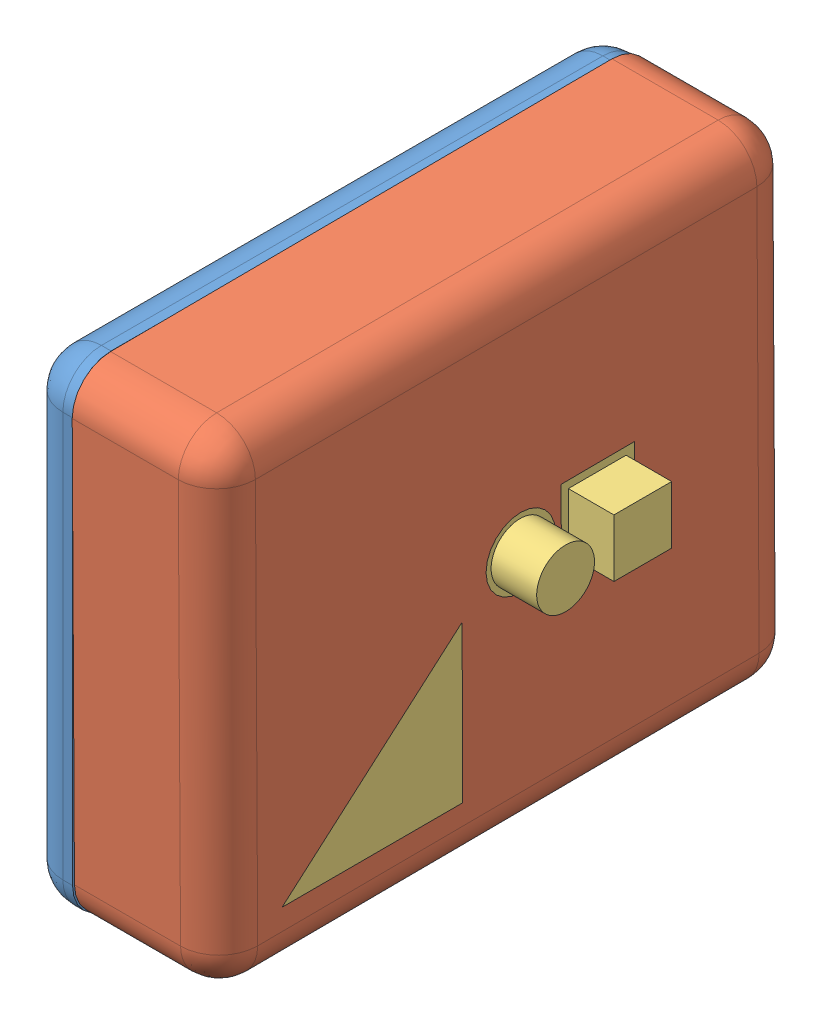
SolidWorks assembly Assem2, configuration Default. Lengths in mm.
Overall size (31.4 63.92 76.55).
3 component instances, 3 part files, 2 mates.
Components (placement in the parent):
- bottom of assembly-1: bottom of assembly [Default] at origin size (8.13 63.5 76.2)
- top of housing-1: top of housing [Default] at (25.4 63.8613 -103.9037) x (0 -0.005555 0.999985) z (0 0.999985 0.005555) size (76.2 19.05 63.5)
- PCB of assembly-1: PCB of assembly [Default] at (22.3977 10.4422 -96.8307) x (0 0.000965 -1) z (1 0 0) size (62.68 48.77 22.76)
Mates (geometry in assembly coordinates):
- Coincident4: coincident: plane of top of housing-1 through (6.35 63.8613 -103.9037) normal (-1 0 0); plane of bottom of assembly-1 through (6.35 0 0) normal (1 0 0)
- Coincident5: coincident: plane of top of housing-1 through (25.4003 63.8613 -103.9037) normal (1 0 0); plane of PCB of assembly-1 through (25.4003 10.4422 -96.8307) normal (1 0 0)
